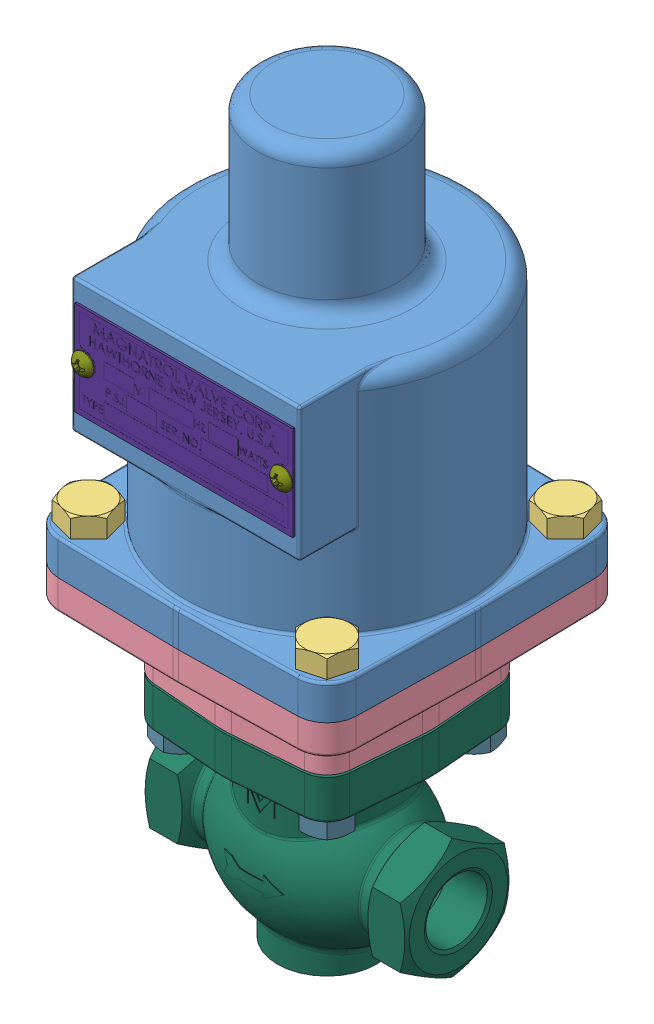
SolidWorks assembly E29LR62SC-GDTZCY, configuration Default. Lengths in mm.
Overall size (101.44 233.26 98.1).
34 component instances, 17 part files, 0 mates.
Components (placement in the parent):
- BV-F29DC-SLR2SC-Z-1: BV-F29DC-SLR2SC-Z [Default] at origin size (101.44 233.26 98.1)
  - CUP-F25-37RDC-SL-1: CUP-F25-37RDC-SL [Default] at origin size (96.84 129.38 96.84)
    - CUP-F25-37RDC-1: CUP-F25-37RDC [Default] at origin size (96.84 129.38 96.84)
      - CASTING-1544-1: CASTING-1544 [Default] at origin size (96.84 129.38 96.84)
    - SLEEVE-33-1: SLEEVE-33 [Default] at (0 46.0756 0) size (31.75 38.89 31.75)
  - BOLT-50SS-1: BOLT-50SS [Default] at (-38.1661 4.7625 38.1661) x (0 -1 0) z (0.707107 0 0.707107) size (25.7 16.5 14.29)
  - BASE-F29DC-SL-1: BASE-F29DC-SL [Default] at (0 -15.0812 0) size (100.81 59.66 96.84)
    - BASE-F29DC-1: BASE-F29DC [Default] at origin size (100.81 30.18 96.84)
    - SLEEVE-33-1: SLEEVE-33 [Default] at (0 44.5707 0) x (-1 0 0) z (0 0 1) size (31.75 38.89 31.75)
  - STOP-33RDC-1: STOP-33RDC [Default] at (0 -30.6832 0) size (28.57 42.06 28.57)
  - PLUNGER-33RDC-1: PLUNGER-33RDC [Default] at (0 23.0378 0) size (23.29 76.99 23.02)
  - BA-F33R2-3-1: BA-F33R2-3 [Default] at (0 100.0252 0) size (48.34 146.08 48.34)
    - BLB-10-1: BLB-10 [Default] at origin size (25.4 134.16 25.4)
      - BLB-ASM10-1: BLB-ASM10 [Default] at origin size (25.4 134.16 25.4)
        - BS-18-33R-1: BS-18-33R [Default] at origin size (25.4 12.7 25.4)
        - BT-33R-SM-1: BT-33R-SM [Default] at (0 -121.4628 0) size (25.4 126.21 25.4)
        - RNG18COP-1: RNG18COP [Default] at (0 -0.5842 0) size (24.13 1.07 24.12)
    - BB-18-33FR2-3-1: BB-18-33FR2-3 [Default] at (0 -134.1628 0) size (48.34 15.88 48.34)
      - FORGING-2522-1: FORGING-2522 [Default] at origin size (48.34 15.88 48.34)
    - RNGSIL18-33-1: RNGSIL18-33 [Default] at (0 -120.9548 0) size (24.13 1.07 24.12)
  - CB-DC-1: CB-DC [Default] at (0 74.6506 0) size (45.32 17.63 42.82)
  - GASKET-23-T-1: GASKET-23-T [Default] at (0 -34.1439 0) size (48.42 0.79 48.42)
  - BOLT-40SS-1: BOLT-40SS [Default] at (-23.5732 -33.6328 23.5732) x (0 1 0) z (0.707107 0 0.707107) size (31.22 14.66 12.7)
  - VB-SLR2SC-1: VB-SLR2SC [Default] at (0 -76.0984 0) size (84.14 73.02 66.68)
    - VB-SL2SC-1: VB-SL2SC [Default] at origin size (84.14 73.02 66.68)
  - BOLT-40SS-2: BOLT-40SS [Default] at (23.5732 -33.6328 23.5732) x (0 1 0) z (0.707107 0 -0.707107) size (31.22 14.66 12.7)
  - BOLT-40SS-3: BOLT-40SS [Default] at (23.5732 -33.6328 -23.5732) x (0 1 0) z (-0.707107 0 -0.707107) size (31.22 14.66 12.7)
  - BOLT-40SS-4: BOLT-40SS [Default] at (-23.5732 -33.6328 -23.5732) x (0 1 0) z (-0.707107 0 0.707107) size (31.22 14.66 12.7)
  - BOLT-50SS-2: BOLT-50SS [Default] at (38.1661 4.7625 38.1661) x (0 -1 0) z (0.707107 0 -0.707107) size (25.7 16.5 14.29)
  - BOLT-50SS-3: BOLT-50SS [Default] at (38.1661 4.7625 -38.1661) x (0 -1 0) z (-0.707107 0 -0.707107) size (25.7 16.5 14.29)
  - BOLT-50SS-4: BOLT-50SS [Default] at (-38.1661 4.7625 -38.1661) x (0 -1 0) z (-0.707107 0 0.707107) size (25.7 16.5 14.29)
  - SCREW-NP-1: SCREW-NP [Default] at (-31.75 61.9125 46.0375) size (6.86 6.88 8.81)
  - SCREW-NP-2: SCREW-NP [Default] at (31.75 61.9125 46.0375) size (6.86 6.88 8.81)
- NP-D-1: NP-D [Default] at (0 61.9125 45.2437) size (69.85 30.18 0.64)
